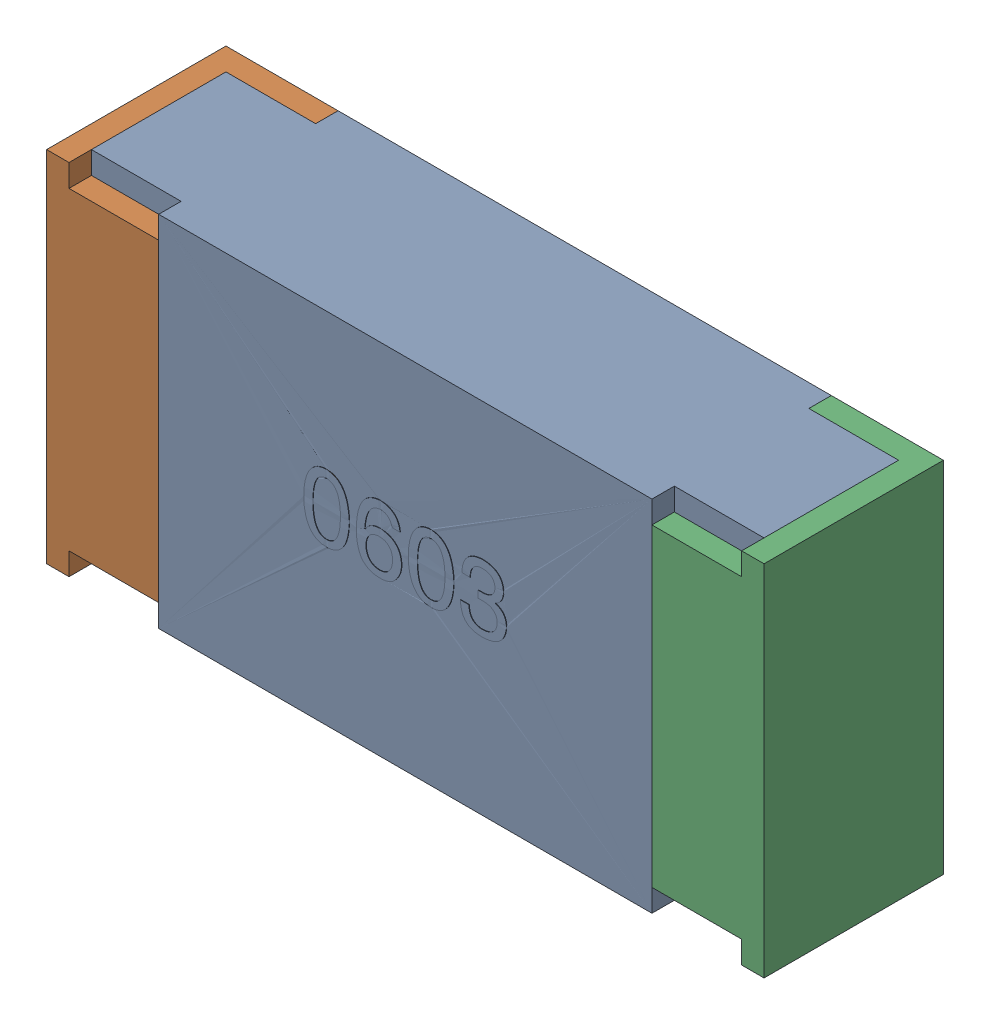
SolidWorks assembly R_0603, configuration 默认. Lengths in mm.
Overall size (1.6 0.8 0.41).
2 component instances, 2 part files, 0 mates.
Components (placement in the parent):
- R_0603-1: R_0603 [默认] at origin size (1.6 0.8 0.41)
- LOGO__2-1: LOGO__2 [默认] at (0.0001 0.0322 -0.0016) x (-1 0 0) z (0 0 -1) size (0.48 0.55 0)
